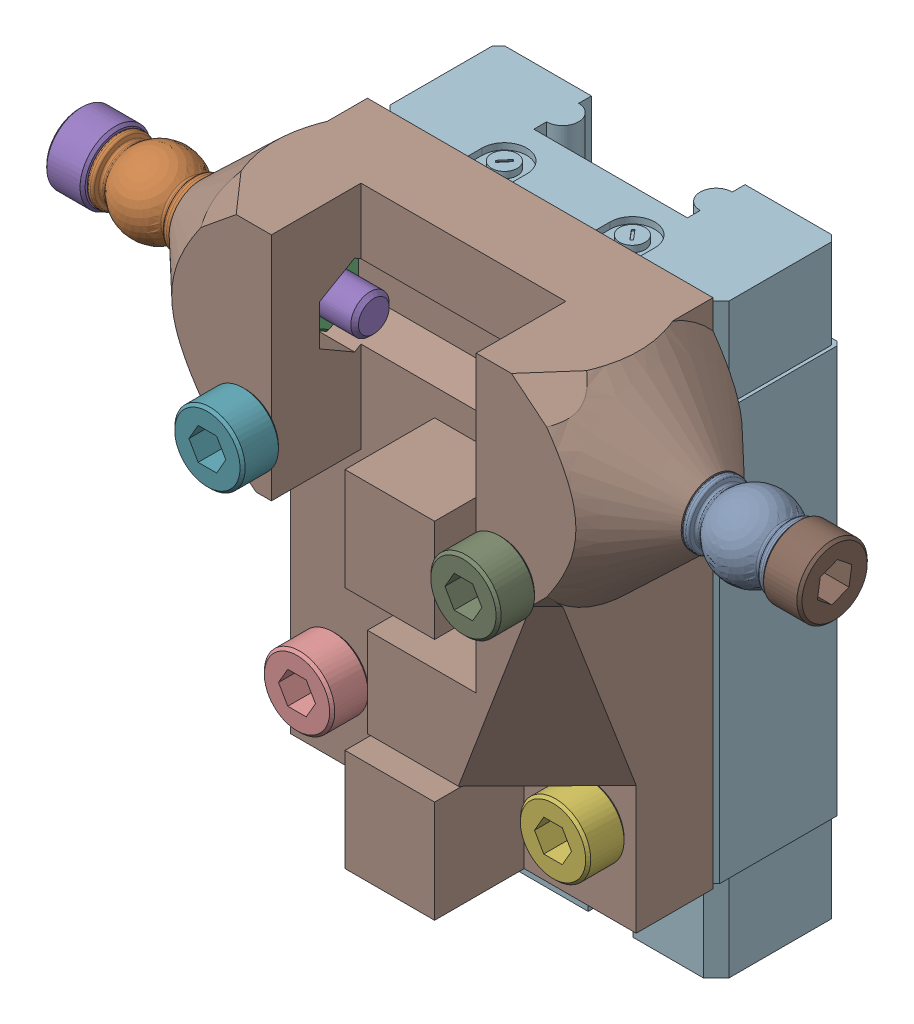
SolidWorks assembly carriage ass-01sw, configuration Default. Lengths in mm.
Overall size (59 47.1 26).
12 component instances, 7 part files, 0 mates.
Components (placement in the parent):
- 5347 Hollow Balls-1: 5347 Hollow Balls [Default] at (26.5 16 0) x (0 0.590322 -0.807168) z (0 0.807168 0.590322) size (6 6.5 6)
- 5347 Hollow Balls-2: 5347 Hollow Balls [Default] at (-20 16 0) x (0 -0.477716 0.878514) z (0 -0.878514 -0.477716) size (6 6.5 6)
- m3 nut-1: m3 nut [Default] at (-12 16 0) x (0 -0.5 -0.866025) z (1 0 0) size (5.77 5 2)
- m3 nut-2: m3 nut [Default] at (12 16 0) x (0 0.5 0.866025) z (-1 0 0) size (5.77 5 2)
- m3x20 socket screw-1: m3x20 socket screw [Default] at (-6.5 16 0) x (0 0.845175 0.534489) z (0 -0.534489 0.845175) size (5.5 23 5.5)
- m3x10 socket screw-1: m3x10 socket screw [Default] at (10 -10 -10.5) x (-0.5 -0.866025 0) z (-0.866025 0.5 0) size (5.5 13 5.5)
- m3x16 socket screw-1: m3x16 socket screw [Default] at (-10 10 -9.5) x (-0.5 -0.866025 0) z (-0.866025 0.5 0) size (5.5 19 5.5)
- carriage sw-1: carriage sw [Default] at origin size (40 40.2 13.2)
- m3x16 socket screw-2: m3x16 socket screw [Default] at (10 10 -9.5) x (1 0 0) z (0 -1 0) size (5.5 19 5.5)
- m3x10 socket screw-2: m3x10 socket screw [Default] at (-10 -10 -10.5) x (-0.5 -0.866025 0) z (-0.866025 0.5 0) size (5.5 13 5.5)
- m3x20 socket screw-2: m3x20 socket screw [Default] at (6.5 16 0) x (0 0.988846 -0.148943) z (0 -0.148943 -0.988846) size (5.5 23 5.5)
- HI_b_SSEBT13-1: HI_b_SSEBT13 [Default] at (1.9099 -25.593 -46.5536) x (1 0 0) z (0 -1 0) size (27 10 45.8)
